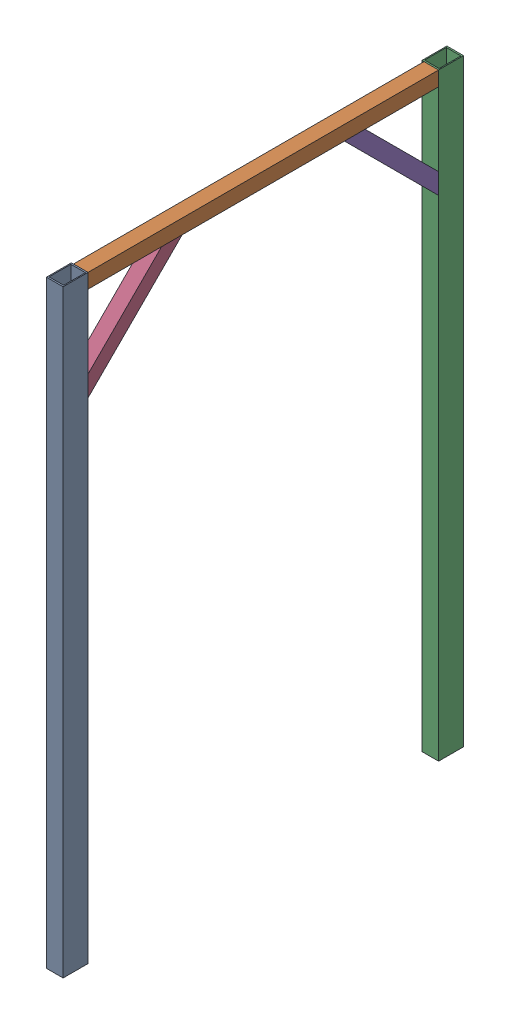
SolidWorks assembly GE-16162_ASM, configuration Default. Lengths in mm.
Overall size (50.8 1828.8 1223.26).
5 component instances, 3 part files, 0 mates.
Components (placement in the parent):
- GE-16162-01-1: GE-16162-01 [Default] at origin size (50.8 1828.8 76.2)
- GE-16162-02-1: GE-16162-02 [Default] at (-19.05 1784.35 -1108.964) size (44.45 44.45 1070.86)
- GE-16162-01-2: GE-16162-01 [Default] at (0 0 -1147.064) x (-1 0 0) z (0 0 -1) size (50.8 1828.8 76.2)
- GE-16162-03-1: GE-16162-03 [Default] at (-19.05 1559.8436 -38.1) x (1 0 0) z (0 0.707107 -0.707107) size (44.45 44.45 406.4)
- GE-16162-03-2: GE-16162-03 [Default] at (-19.05 1784.35 -884.4576) x (1 0 0) z (0 -0.707107 -0.707107) size (44.45 44.45 406.4)
